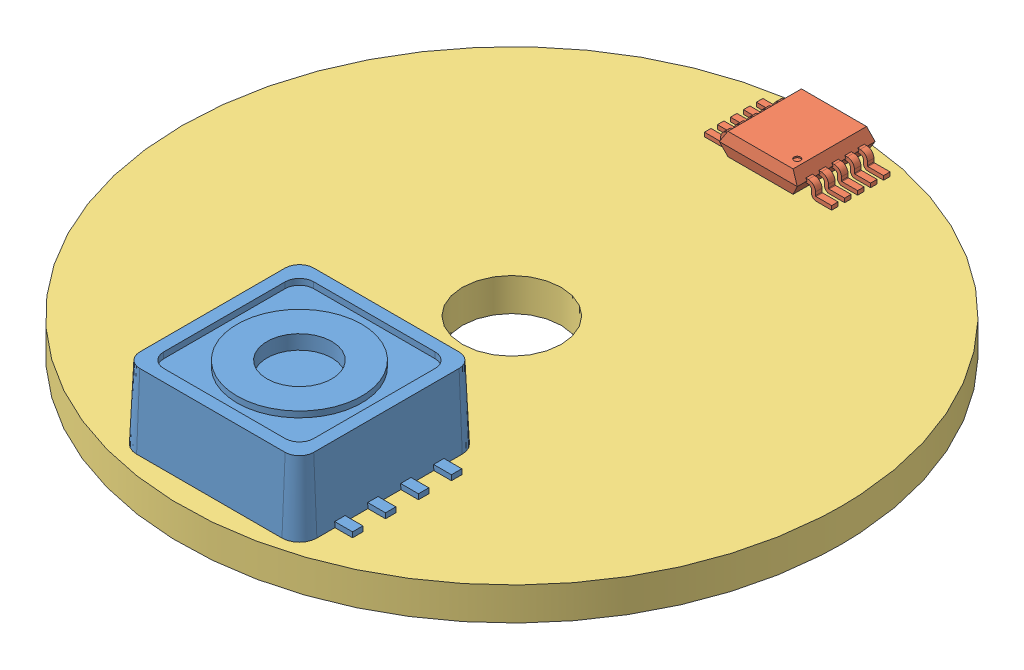
SolidWorks assembly ADC and pressure sensor, configuration sameSide. Lengths in mm.
Overall size (25.4 4.07 25.4).
3 component instances, 3 part files, 10 mates.
Components (placement in the parent):
- Pressure Sensor-1: Pressure Sensor [Default] at origin
- ADC-1: ADC [Default] at (0 -0.8975 -19.1772) x (-1 0 0) z (0 0 -1)
- Part3^ADC and pressure sensor-1: Part3^ADC and pressure sensor [Default] at (-0.1878 -2.67 -8.3684) x (1 0 0) z (0 1 0) (virtual)
Mates (geometry in assembly coordinates):
- Coincident7: coincident anti-aligned: plane of Pressure Sensor-1 through (0 -1.4 0) normal (0 -1 0); plane of Part3^ADC and pressure sensor-1 through (-0.1878 -1.4 -8.3684) normal (0 1 0)
- Concentric1: concentric aligned: circle of Pressure Sensor-1; circle of Part3^ADC and pressure sensor-1
- Coincident8: coincident anti-aligned: plane of ADC-1; plane of Part3^ADC and pressure sensor-1 through (0 -2.67 0) normal (0 -1 0)
- Coincident9: coincident aligned: plane of ADC-1; plane of assembly through (0 0 0) normal (0 0 1)
- Coincident10: coincident anti-aligned: plane of ADC-1 through (0 -3.1725 0) normal (-1 0 0); plane of assembly through (0 0 0) normal (1 0 0)
- Coincident11: coincident anti-aligned: plane of ADC-1 through (1.85 -1.4 -19.8022) normal (0 -1 0); plane of Part3^ADC and pressure sensor-1 through (-0.1878 -1.4 -8.3684) normal (0 1 0)
- Parallel1: parallel anti-aligned: plane of Pressure Sensor-1 through (0 0 0) normal (0 0 1); plane of ADC-1 through (0 -0.8975 -19.1772) normal (0 0 -1)
- Coincident15: coincident anti-aligned: plane of Pressure Sensor-1 through (0 0 0) normal (1 0 0); plane of ADC-1 through (0 -0.8975 -19.1772) normal (-1 0 0)
- Lock1: lock: unknown of ADC-1; unknown of Part3^ADC and pressure sensor-1
- Lock2: lock: unknown of Pressure Sensor-1; unknown of Part3^ADC and pressure sensor-1
